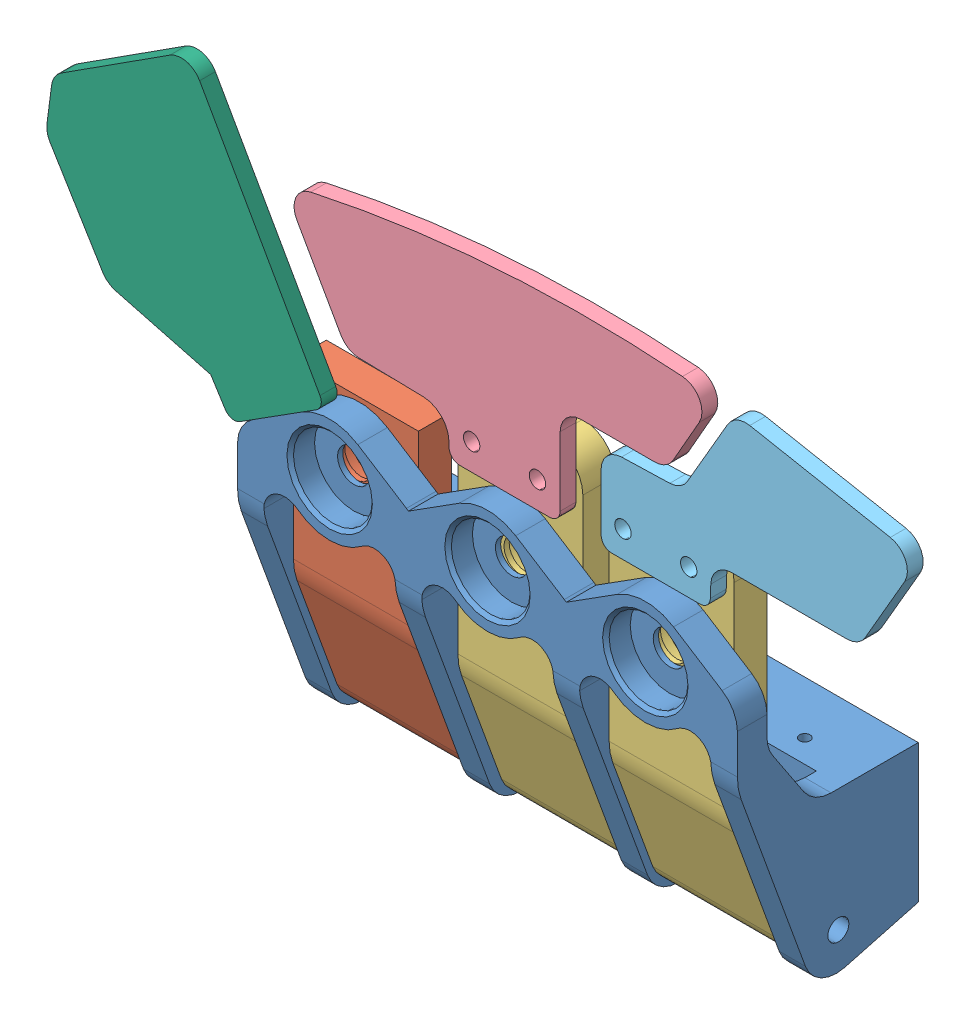
SolidWorks assembly triple assem, configuration Default. Lengths in mm.
Overall size (128.77 85.83 27.5).
7 component instances, 6 part files, 17 mates.
Components (placement in the parent):
- triple-1: triple [Default] at (16.5455 38.7329 65.206) size (76 49.55 27.5)
- clutch shifter lever-1: clutch shifter lever [Default] at (51.3979 106.7431 134.2981) size (67 58.15 15.35)
- Step_MS01_-_Shifter_Lever-2: Step_MS01_-_Shifter_Lever [Default] at (76.3979 106.7431 134.2981) size (19 58.15 15.35)
- Step_MS01_-_Shifter_Lever-3: Step_MS01_-_Shifter_Lever [Default] at (99.3979 106.7431 134.2981) size (19 58.15 15.35)
- middleLeftPaddle-1: middleLeftPaddle [Default] at (-260.7548 836.2463 156.2124) x (0 -1 0) z (0 0 1) size (29.18 62.03 2.4)
- topLeftPaddle-1: topLeftPaddle [Default] at (-268.7359 836.9444 156.2124) x (0 -1 0) z (0 0 1) size (27.36 46.57 2.4)
- clutch-2: clutch [Default] at (-250.3883 835.7948 158.3124) x (-0.000542 -1 0) z (0 0 1) size (43.7 41.76 2.4)
Mates (geometry in assembly coordinates):
- Concentric1: concentric aligned: cylinder of triple-1 through (65.8979 83.8979 148.6586) axis (-1 0 0) radius 1.6; cylinder of clutch shifter lever-1 through (60.8979 83.8979 148.6586) axis (-1 0 0) radius 2.75
- Coincident1: coincident anti-aligned: plane of triple-1 through (41.8979 93.0842 153.7729) normal (1 0 0); plane of clutch shifter lever-1 through (41.8979 108.4745 151.8355) normal (-1 0 0)
- Coincident2: coincident anti-aligned: plane of triple-1 through (51.8979 117.9714 159.5124) normal (0 0 -1); plane of clutch shifter lever-1 through (60.8979 114.3497 159.5124) normal (0 0 1)
- Concentric2: concentric aligned: circle of triple-1; circle of Step_MS01_-_Shifter_Lever-2
- Coincident3: coincident anti-aligned: plane of triple-1 through (85.8979 93.0842 153.7729) normal (-1 0 0); plane of Step_MS01_-_Shifter_Lever-2 through (85.8979 108.4745 151.8355) normal (1 0 0)
- Coincident4: coincident anti-aligned: plane of triple-1 through (51.8979 117.9714 159.5124) normal (0 0 -1); plane of Step_MS01_-_Shifter_Lever-2 through (85.8979 114.3497 159.5124) normal (0 0 1)
- Concentric3: concentric anti-aligned: cylinder of triple-1 through (113.8979 83.8979 148.6586) axis (-1 0 0) radius 1.6; circle of Step_MS01_-_Shifter_Lever-3
- Coincident5: coincident anti-aligned: plane of triple-1 through (89.8979 102.9745 150.5124) normal (1 0 0); plane of Step_MS01_-_Shifter_Lever-3 through (89.8979 108.4745 151.8355) normal (-1 0 0)
- Coincident6: coincident anti-aligned: plane of triple-1 through (51.8979 117.9714 159.5124) normal (0 0 -1); plane of Step_MS01_-_Shifter_Lever-3 through (108.8979 114.3497 159.5124) normal (0 0 1)
- Coincident7: coincident aligned: circle of Step_MS01_-_Shifter_Lever-2; circle of middleLeftPaddle-1
- Coincident8: coincident aligned: circle of Step_MS01_-_Shifter_Lever-2; circle of middleLeftPaddle-1
- Coincident9: coincident aligned: circle of Step_MS01_-_Shifter_Lever-3; circle of topLeftPaddle-1
- Coincident11: coincident aligned: circle of Step_MS01_-_Shifter_Lever-3; circle of topLeftPaddle-1
- Coincident12: coincident: plane of clutch shifter lever-1 through (60.8979 114.3497 159.5124) normal (0 0 1); plane of clutch-1 through (139.4977 739.7909 159.5124) normal (0 0 -1)
- Coincident13: coincident aligned: line of clutch shifter lever-1 through (27.2545 128.4748 159.5124) axis (1 0 0); line of clutch-1 through (27.3253 128.4748 159.5124) axis (1 0 0)
- Coincident15: coincident anti-aligned: plane of triple-1 through (43.7818 124.1698 159.5124) normal (-0.535714 0.844399 0); plane of clutch-2 through (51.183 128.8653 164.0124) normal (0.535714 -0.844399 0)
- Coincident16: coincident aligned: plane of triple-1 through (65.8979 119.8447 164.0124) normal (0 0 1); plane of clutch-2 through (-194.5288 696.9435 164.0124) normal (0 0 1)
